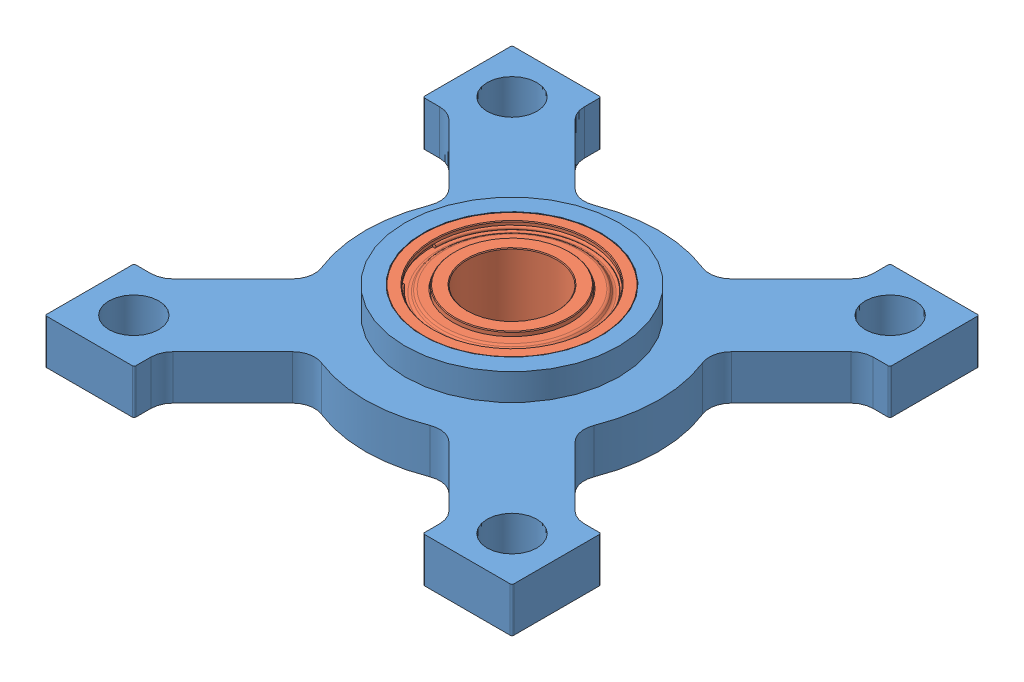
SolidWorks assembly 535110 assembly - Pillow1, configuration Default. Lengths in mm.
Overall size (33.27 5.08 33.27).
2 component instances, 2 part files, 0 mates.
Components (placement in the parent):
- 535110-1: 535110 [Default] at (6.6273 15.2478 28.3097) size (33.27 5.08 33.27)
- 535020_1-1: 535020_1 [Default] at (6.6273 17.9338 28.3097) size (12.7 4.76 12.7)
